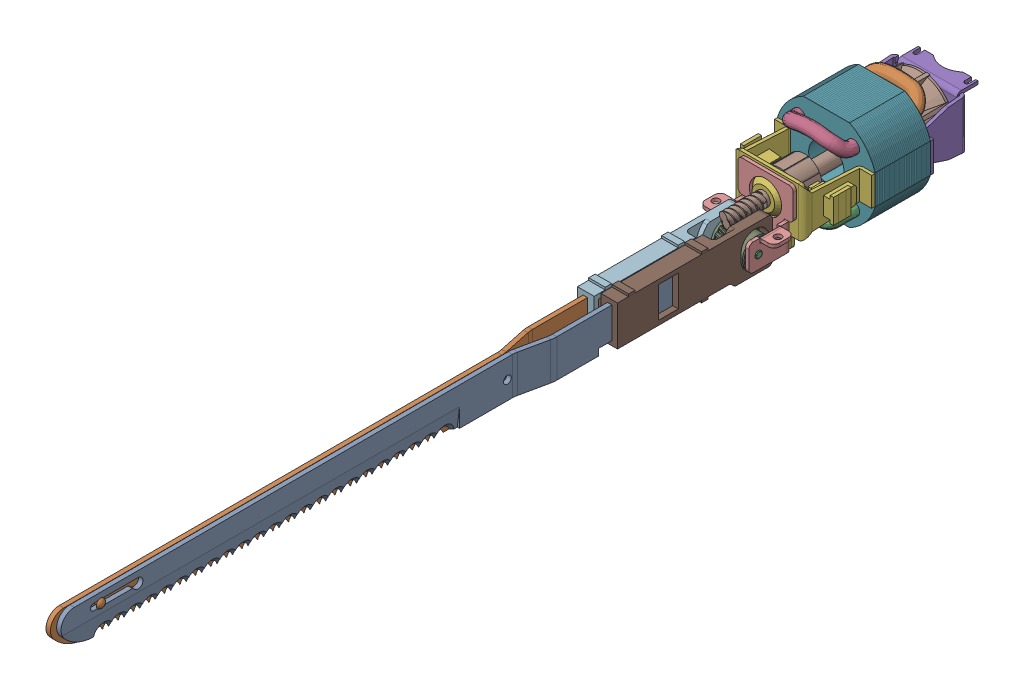
SolidWorks assembly Knife Mechanism, configuration Default. Lengths in mm.
Overall size (44 44.55 405.46).
9 component instances, 9 part files, 23 mates.
Components (placement in the parent):
- motor-1: motor [Default] at origin size (44 41 83.5)
- shaft-1: shaft [Default] at (0 0 53.5) x (0.857131 0.515098 0) z (0 0 1) size (31.13 31.13 96.88)
- Gear-1: Gear [Default] at (0 -10.3187 53.7366) x (1 0 0) z (0 0.542743 0.839899) size (17.46 18.38 18.37)
- Gear Mount-1: Gear Mount [Default] at (0 0 38.5) size (33.55 26.32 19.5)
- Left Knife Sleeve-1: Left Knife Sleeve [Default] at (5.1912 -10.3187 52.4033) size (7.54 21 70)
- Right Knife Sleeve-2: Right Knife Sleeve [Default] at (4.8087 -10.3187 55.0699) size (7.54 21 70)
- Left Blade-1: Left Blade [Default] at (-5.0496 -19.3187 70.6033) x (0 0 -1) z (1 0 0) size (289.69 17 5.12)
- Right Blade-1: Right Blade [Default] at (-5.1912 -19.3187 73.2699) x (0 0 -1) z (1 0 0) size (289.69 17 8.64)
- Gear Rod-1: Gear Rod [Default] at (6 -10.3187 53.7366) x (1 0 0) z (0 -0.489933 0.87176) size (23 3.17 3.17)
Mates (geometry in assembly coordinates):
- Concentric1: concentric aligned: cylinder of shaft-1 through (0 0 75.725) axis (0 0 1) radius 3.175; cone of motor-1 through (0 0 38.5) axis (0 0 1)
- Tangent1: tangent anti-aligned: cylinder of gear-1 through (8.7312 -11.1804 52.4033) axis (-1 0 0) radius 6.35; plane of left knife sleeve-1 through (7.7313 -8.7312 46.0533) normal (0 0 1)
- Distance1: distance = 0.5 mm aligned: plane of motor-1 through (0 0 -37) normal (0 0 -1); plane of shaft-1 through (0 0 -37.5) normal (0 0 -1)
- Coincident3: coincident aligned: plane of gear-1 through (0 -10.3187 53.7366) normal (1 0 0); plane of assembly through (0 0 0) normal (1 0 0)
- GearMate1: gear = 0.01 : 0.001: cylinder of shaft-1 through (0 0 75.725) axis (0 0 1) radius 3.175; cylinder of gear-1 through (2.3813 -10.3187 53.7366) axis (-1 0 0) radius 7.9375
- InPlace1: in place: moOrthogonalPlaneRef_w of motor-1 through (-16.5 -11 38.5) normal (0 0 1); unknown of gear mount-1
- Coincident5: coincident aligned: plane of ?; plane of ?
- Coincident6: coincident aligned: moOrthogonalPlaneRef_w of motor-1 through (0 0 38.5) axis (0 1 0); plane of gear mount-1 through (0 0 38.5) normal (0 1 0)
- Coincident7: coincident anti-aligned: moOrthogonalPlaneRef_w of motor-1 through (0 0 38.5) axis (-1 0 0); plane of gear mount-1 through (0 0 38.5) normal (1 0 0)
- Concentric3: concentric aligned: cylinder of gear-1 through (-13.0378 -10.3187 53.7366) axis (1 0 0) radius 1.5875; cylinder of gear mount-1 through (-12.5 -10.3187 53.7366) axis (1 0 0) radius 1.5
- Coincident8: coincident aligned: plane of gear mount-1 through (0 -10.3187 38.5) normal (0 1 0); plane of left knife sleeve-1 through (5.1912 -10.3187 52.4033) normal (0 1 0)
- Distance2: distance = 1 mm aligned: plane of gear-1 through (8.7312 -11.1804 52.4033) normal (1 0 0); plane of left knife sleeve-1 through (7.7313 -0.3188 114.5533) normal (1 0 0)
- Coincident12: coincident anti-aligned: plane of left knife sleeve-1 through (5.1912 -0.3188 114.5533) normal (-1 0 0); plane of left blade-1 through (5.1912 0.6813 343.8795) normal (1 0 0)
- Coincident14: coincident anti-aligned: plane of left knife sleeve-1 through (0.1912 -2.3188 70.6033) normal (0 0 1); plane of left blade-1 through (3.1913 -2.3188 70.6033) normal (0 0 -1)
- Coincident15: coincident anti-aligned: plane of left knife sleeve-1 through (0.1912 -2.3188 70.6033) normal (0 -1 0); plane of left blade-1 through (3.1913 -2.3188 354.6033) normal (0 1 0)
- Distance4: distance = 1 mm aligned: plane of gear-1 through (-8.7312 -9.4571 55.0699) normal (-1 0 0); plane of right knife sleeve-2 through (-7.7313 -0.3188 117.2199) normal (-1 0 0)
- Coincident17: coincident anti-aligned: plane of right knife sleeve-2 through (-5.1912 -0.3188 117.2199) normal (1 0 0); plane of right blade-1 through (-5.1912 0.6813 346.5461) normal (-1 0 0)
- Coincident18: coincident: plane of right knife sleeve-2 through (-0.1912 -2.3188 73.2699) normal (0 -1 0); line of right blade-1 through (-3.1913 -2.3188 73.2699) axis (0 0 1)
- Coincident19: coincident anti-aligned: plane of right knife sleeve-2 through (-0.1912 -2.3188 73.2699) normal (0 0 1); plane of right blade-1 through (-3.1913 -2.3188 73.2699) normal (0 0 -1)
- Coincident20: coincident aligned: plane of gear mount-1 through (0 -10.3187 38.5) normal (0 1 0); plane of right knife sleeve-2 through (4.8087 -10.3187 55.0699) normal (0 1 0)
- Tangent2: tangent anti-aligned: cylinder of gear-1 through (-8.7312 -9.4571 55.0699) axis (1 0 0) radius 6.35; plane of right knife sleeve-2 through (-7.7313 -8.7312 61.4199) normal (0 0 -1)
- Concentric4: concentric aligned: cylinder of gear mount-1 through (-12.5 -10.3187 53.7366) axis (1 0 0) radius 1.5; cylinder of gear rod-1 through (-12 -10.3187 53.7366) axis (1 0 0) radius 1.5
- Distance5: distance = 0.5 mm aligned: plane of gear mount-1 through (10.5 -16.3188 58) normal (1 0 0); plane of gear rod-1 through (11 -10.3187 53.7366) normal (1 0 0)
